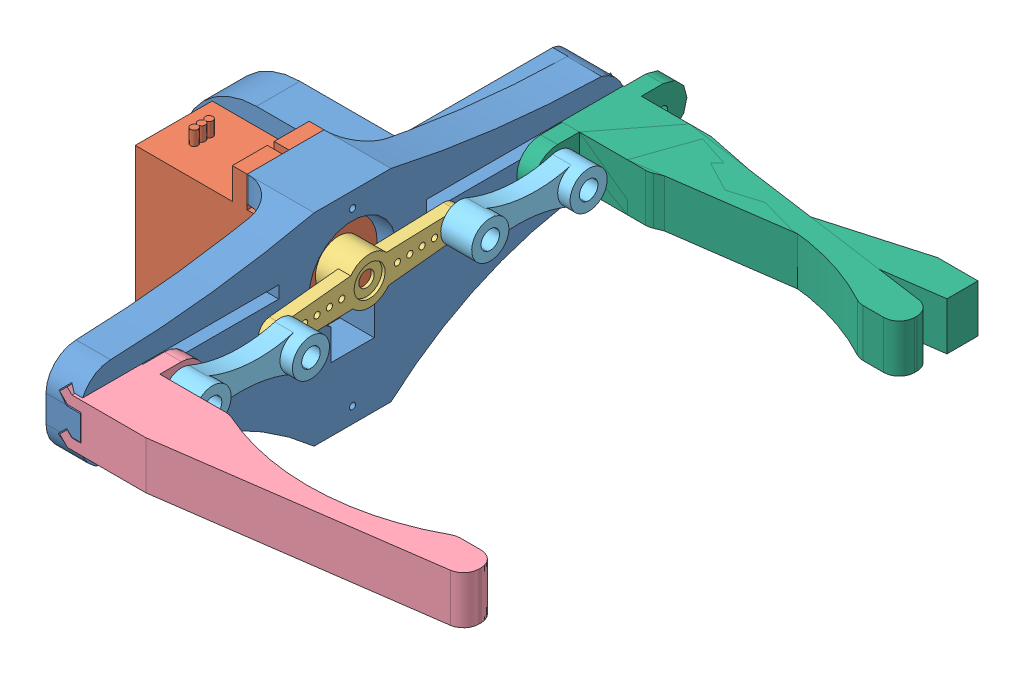
SolidWorks assembly Linear Gripper, configuration Default. Lengths in mm.
Overall size (91.53 33.39 87.8).
7 component instances, 6 part files, 16 mates.
Components (placement in the parent):
- Linear Base-1: Linear Base [Default] at origin size (35.83 33.39 87.8)
- Servo Micro-2: Servo Micro [Default] at (-5.15 0.0047 15.2) x (0 -1 0) z (0 0 1) size (32.6 29.9 12.4)
- Horn-1: Horn [По умолчанию] at (26.45 5.1047 15.2) x (0 0.069042 -0.997614) z (-1 0 0) size (32 7.5 5)
- LGrip-1: LGrip [Default] at (23.7 3.1845 54.0339) x (0 0 -1) z (1 0 0) size (17.35 8.47 59.1)
- Linear Link-1: Linear Link [Default] at (29.45 4.6042 37.5996) x (0 -0.062963 -0.998016) z (0 0.998016 -0.062963) size (21.9 5 6)
- Linear Link-2: Linear Link [Default] at (29.45 5.6053 -7.1996) x (0 -0.062963 -0.998016) z (0 0.998016 -0.062963) size (21.9 5 6)
- LGrip Mirror-1: LGrip Mirror [Default] at (23.7 3.1845 -23.6339) x (0 0 -1) z (1 0 0) size (24.7 8.47 59.1)
Mates (geometry in assembly coordinates):
- Parallel1: parallel aligned: plane of Linear Base-1 through (4.3155 0 7) normal (0 0 1); plane of Servo Micro-2 through (17.15 11.3047 21.4) normal (0 0 1)
- Coincident8: coincident anti-aligned: plane of Linear Base-1 through (12.9 16.3047 21.4) normal (-1 0 0); plane of Servo Micro-2 through (12.9 16.3047 21.4) normal (1 0 0)
- Concentric2: concentric anti-aligned: circle of Servo Micro-2; circle of Horn-1
- Coincident11: coincident anti-aligned: plane of Servo Micro-2 through (21.45 0.0047 15.2) normal (1 0 0); plane of Horn-1 through (21.45 5.1047 15.2) normal (-1 0 0)
- Concentric3: concentric aligned: circle of Linear Base-1; circle of Servo Micro-2
- Coincident12: coincident anti-aligned: plane of Linear Base-1 through (23.7 0 -23) normal (1 0 0); plane of LGrip-1 through (23.7 3.1845 54.0339) normal (-1 0 0)
- Distance3: distance = 0.15 mm anti-aligned: plane of Linear Base-1 through (0 9.1047 27.1) normal (0 -1 0); plane of LGrip-1 through (23.55 8.9547 44.8319) normal (0 1 0)
- Concentric4: concentric anti-aligned: circle of LGrap-1; circle of Linear Link-1
- Concentric5: concentric aligned: circle of Horn-1; circle of Linear Link-1
- Coincident17: coincident anti-aligned: plane of Horn-1 through (26.45 5.1047 15.2) normal (1 0 0); plane of Linear Link-1 through (26.45 5.1047 45.5339) normal (-1 0 0)
- LimitDistance1: limit distance = 21.9339 mm anti-aligned: plane of LGrip-1 through (28.7 -2.6337 49.0339) normal (0 0 -1); plane of Linear Base-1 through (0 0 27.1) normal (0 0 1)
- Concentric6: concentric anti-aligned: circle of Horn-1; circle of Linear Link-2
- Coincident20: coincident anti-aligned: plane of Horn-1 through (26.45 5.1047 15.2) normal (1 0 0); plane of Linear Link-2 through (26.45 6.1058 0.7346) normal (-1 0 0)
- Coincident21: coincident anti-aligned: plane of Linear Base-1 through (23.7 0 -23) normal (1 0 0); plane of LGrip Mirror-1 through (23.7 3.1845 -23.6339) normal (-1 0 0)
- Distance4: distance = 0.15 mm anti-aligned: plane of LGrip Mirror-1 through (23.55 8.9547 -14.4319) normal (0 1 0); plane of Linear Base-1 through (0 9.1047 3.3) normal (0 -1 0)
- Concentric7: concentric aligned: circle of Linear Link-2; circle of LGrip Mirror-1
